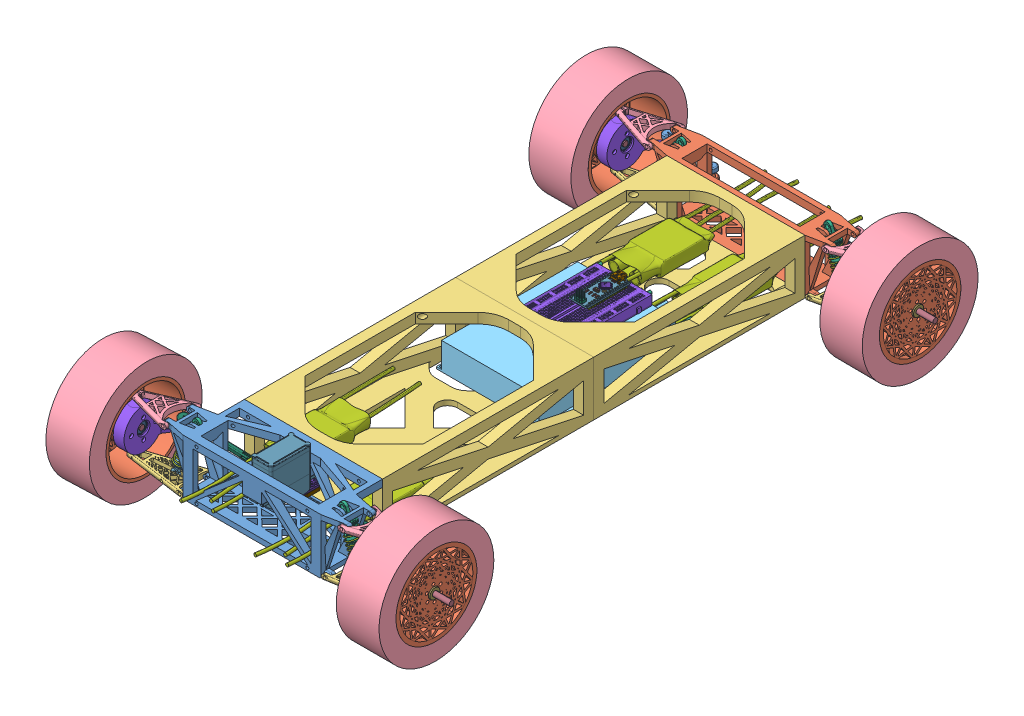
SolidWorks assembly corr, configuration Default. Lengths in mm.
Overall size (361.58 158.9 635.76).
113 component instances, 44 part files, 87 mates.
Components (placement in the parent):
- front subframe-1: front subframe [Default] at (44.8568 124.9262 411.3933) x (0 0 -1) z (1 0 0) size (61.1 55 184.24)
- rear subframe-1: rear subframe [Default] at (250.5037 124.9262 -151.6436) x (0 0 1) z (-1 0 0) size (45 55 184.24)
- lower_control_arm_front-1: lower_control_arm_front [Default] at (12.1352 184.7934 -110.1751) x (0 0 -1) z (-0.99961 -0.027933 0) size (37.5 5.03 71.27)
- lower_control_arm_front-2: lower_control_arm_front [Default] at (12.207 180.9628 369.9249) x (0 0 -1) z (-0.99611 -0.08812 0) size (37.5 5.03 71.27)
- lower_control_arm_front-3: lower_control_arm_front [Default] at (283.1703 186.8095 -110.1751) x (0 0 1) z (0.999993 0.003801 0) size (37.5 5.03 71.27)
- lower_control_arm_front-4: lower_control_arm_front [Default] at (283.2294 183.9874 369.9249) x (0 0 1) z (0.999175 -0.040609 0) size (37.5 5.03 71.27)
- upper_control_arm_front-1: upper_control_arm_front [Default] at (15.5255 232.3308 -110.1751) x (0 0 1) z (-0.999846 0.017523 0) size (35.03 5.03 51.52)
- upper_control_arm_front-2: upper_control_arm_front [Default] at (15.8477 228.503 369.9249) x (0 0 1) z (-0.997504 -0.070606 0) size (35.03 5.03 51.52)
- upper_control_arm_front-3: upper_control_arm_front [Default] at (279.7954 231.5247 369.9249) x (0 0 -1) z (1 -0.000997 0) size (35.03 5.03 51.52)
- upper_control_arm_front-4: upper_control_arm_front [Default] at (279.8688 234.3481 -110.1751) x (0 0 -1) z (0.997963 0.06379 0) size (35.03 5.03 51.52)
- coilover-1: coilover [Default] at (40.225 170.2681 389.3312) x (0.928908 -0.37031 0) z (0.37031 0.928908 0) size (15.15 15.15 65.67)
  - strut bottom-1: strut bottom [Default] at (8.2738 19.4064 16.0769) size (13 13 37)
  - strut top-1: strut top [Default] at (8.2738 20.4064 60.2501) x (0.996359 -0.085262 0) z (0.085262 0.996359 0) size (14.01 35 14.01)
  - spring-1: spring [Default] at (8.2738 20.4064 29.0769) x (1 0 0) z (0 -1 0) size (13.4 33.17 15.01)
- coilover-2: coilover [Default] at (239.504 166.1902 -90.7688) x (0.935849 0.352401 0) z (-0.352401 0.935849 0) size (15.15 15.15 65.67)
  - strut bottom-1: strut bottom [Default] at (8.2738 19.4064 16.0769) size (13 13 37)
  - strut top-1: strut top [Default] at (8.2738 20.4064 60.2501) x (0.996359 -0.085262 0) z (0.085262 0.996359 0) size (14.01 35 14.01)
  - spring-1: spring [Default] at (8.2738 20.4064 29.0769) x (1 0 0) z (0 -1 0) size (13.4 33.17 15.01)
- coilover-3: coilover [Default] at (255.1275 171.2229 348.5185) x (-0.931225 -0.364446 0) z (-0.364446 0.931225 0) size (15.15 15.15 65.67)
  - strut bottom-1: strut bottom [Default] at (8.2738 19.4064 16.0769) size (13 13 37)
  - strut top-1: strut top [Default] at (8.2738 20.4064 60.2501) x (0.996359 -0.085262 0) z (0.085262 0.996359 0) size (14.01 35 14.01)
  - spring-1: spring [Default] at (8.2738 20.4064 29.0769) x (1 0 0) z (0 -1 0) size (13.4 33.17 15.01)
- coilover-4: coilover [Default] at (40.0876 171.6564 -90.7688) x (0.926996 -0.375072 0) z (0.375072 0.926996 0) size (15.15 15.15 65.67)
  - strut bottom-1: strut bottom [Default] at (8.2738 19.4064 16.0769) size (13 13 37)
  - strut top-1: strut top [Default] at (8.2738 20.4064 60.2501) x (0.996359 -0.085262 0) z (0.085262 0.996359 0) size (14.01 35 14.01)
  - spring-1: spring [Default] at (8.2738 20.4064 29.0769) x (1 0 0) z (0 -1 0) size (13.4 33.17 15.01)
- pside_front_knuckle-1: pside_front_knuckle [Default] at (20.5945 204.7916 369.7511) x (0.008771 -0.999959 -0.002056) z (-0.026502 0.001823 -0.999647) size (55 23.73 55.17)
- pside_front_knuckle-2: pside_front_knuckle [Default] at (20.4171 208.6285 -110.1416) x (0.010097 -0.999949 0.000397) z (0.005118 -0.000345 -0.999987) size (55 23.73 55.17)
- dside_front_knuckle-1: dside_front_knuckle [Default] at (274.9294 207.8222 369.9864) x (-0.01 -0.99995 0.000728) z (-0.009385 -0.000634 -0.999956) size (55 23.73 55.17)
- dside_front_knuckle-2: dside_front_knuckle [Default] at (274.9235 210.6426 -110.1646) x (-0.009923 -0.999951 0.000125) z (-0.001612 -0.000109 -0.999999) size (55 23.73 55.17)
- d3536-1: d3536 [Default] at (8.3914 187.1271 354.2371) x (0.026502 -0.001823 0.999647) z (-0.008771 0.999959 0.002056) size (46.45 53.5 46.45)
  - bottom_case-1: bottom_case [Default] at (15.7997 3.4433 17.5887) size (35 8.57 35)
  - middle_case-1: middle_case [Default] at (15.7997 -15.0567 17.5887) x (-0.998365 0 0.05716) z (-0.05716 0 -0.998365) size (35 18 35)
  - top_case-1: top_case [Default] at (15.7997 -15.0567 17.5887) x (-0.907758 0 0.419495) z (0.419495 0 0.907758) size (35 9.5 35)
  - shaft-1: shaft [Default] at (15.7997 -41.0567 17.5887) x (-0.024609 0 -0.999697) z (0.999697 0 -0.024609) size (5 53.5 5)
- d3536-2: d3536 [Default] at (286.7172 192.938 -94.3819) x (-0.001612 -0.000109 -0.999999) z (0.009923 0.999951 -0.000125) size (46.45 53.5 46.45)
  - bottom_case-1: bottom_case [Default] at (15.7997 3.4433 17.5887) size (35 8.57 35)
  - middle_case-1: middle_case [Default] at (15.7997 -15.0567 17.5887) x (-0.998365 0 0.05716) z (-0.05716 0 -0.998365) size (35 18 35)
  - top_case-1: top_case [Default] at (15.7997 -15.0567 17.5887) x (-0.907758 0 0.419495) z (0.419495 0 0.907758) size (35 9.5 35)
  - shaft-1: shaft [Default] at (15.7997 -41.0567 17.5887) x (-0.024609 0 -0.999697) z (0.999697 0 -0.024609) size (5 53.5 5)
- d3536-3: d3536 [Default] at (8.733 190.9146 -125.9952) x (-0.005118 0.000345 0.999987) z (-0.010097 0.999949 -0.000397) size (46.45 53.5 46.45)
  - bottom_case-1: bottom_case [Default] at (15.7997 3.4433 17.5887) size (35 8.57 35)
  - middle_case-1: middle_case [Default] at (15.7997 -15.0567 17.5887) x (-0.998365 0 0.05716) z (-0.05716 0 -0.998365) size (35 18 35)
  - top_case-1: top_case [Default] at (15.7997 -15.0567 17.5887) x (-0.907758 0 0.419495) z (0.419495 0 0.907758) size (35 9.5 35)
  - shaft-1: shaft [Default] at (15.7997 -41.0567 17.5887) x (-0.024609 0 -0.999697) z (0.999697 0 -0.024609) size (5 53.5 5)
- d3536-4: d3536 [Default] at (286.844 190.1249 385.6862) x (-0.009385 -0.000634 -0.999956) z (0.01 0.99995 -0.000728) size (46.45 53.5 46.45)
  - bottom_case-1: bottom_case [Default] at (15.7997 3.4433 17.5887) size (35 8.57 35)
  - middle_case-1: middle_case [Default] at (15.7997 -15.0567 17.5887) x (-0.998365 0 0.05716) z (-0.05716 0 -0.998365) size (35 18 35)
  - top_case-1: top_case [Default] at (15.7997 -15.0567 17.5887) x (-0.907758 0 0.419495) z (0.419495 0 0.907758) size (35 9.5 35)
  - shaft-1: shaft [Default] at (15.7997 -41.0567 17.5887) x (-0.024609 0 -0.999697) z (0.999697 0 -0.024609) size (5 53.5 5)
- LewanSoul LD-20M  Servo 20kg-1: LewanSoul LD-20M  Servo 20kg [Default] at (147.6802 243.8348 358.3749) x (0 0 -1) z (-1 0 0) size (55.1 45.65 20.12)
- steering arm link-1: steering arm link [Default] at (230.7612 202.8931 337.2388) x (0.99528 0.093085 0.027436) z (0.008631 0.196686 -0.980429) size (77 5 9)
- steering arm link-2: steering arm link [Default] at (63.5262 201.4549 336.7754) x (0.998595 -0.049529 -0.018834) z (-0.011198 0.15015 -0.9886) size (77 5 9)
- steering arm center-1: steering arm center [Default] at (147.2842 186.5681 335.5749) size (109 12 9)
- Servo Mount - Arm Metal Standard-1: Servo Mount - Arm Metal Standard [Défaut] at (147.6802 196.3848 348.4249) x (0.999935 0 -0.011364) z (0 1 0) size (12.43 33.73 5.41)
- steering servo attachment-1: steering servo attachment [Default] at (147.6802 196.3848 348.4249) x (-0.999935 0 0.011364) z (0 -1 0) size (7.5 19.25 3.5)
- rear toe arm-1: rear toe arm [Default] at (238.3086 209.8989 -137.8087) x (0.982379 -0.033336 -0.183902) z (-0.184459 -0.01443 -0.982734) size (64 5 9)
- rear toe arm-2: rear toe arm [Default] at (56.9268 208.879 -137.6028) x (0.980643 0.070066 0.182838) z (0.180365 0.040187 -0.982778) size (64 5 9)
- 8th scale wheel-2: 8th scale wheel [Default] at (309.9261 207.472 369.6581) x (0.01095 0.170873 0.985232) z (-0.999906 0.010006 0.009378) size (89 89 42)
- 8th scale wheel-3: 8th scale wheel [Default] at (309.9218 210.2953 -110.2209) x (-0.006592 -0.768145 0.640241) z (-0.999949 0.009923 0.00161) size (89 89 42)
- 8th scale wheel-4: 8th scale wheel [Default] at (-14.5806 208.275 -110.3206) x (0.003324 0.169907 -0.985454) z (0.999936 0.010099 0.005114) size (89 89 42)
- 8th scale wheel-5: 8th scale wheel [Default] at (-14.3918 204.4828 370.6781) x (-0.010227 -0.767055 -0.6415) z (0.99961 0.008822 -0.026485) size (89 89 42)
- middle subframe-4: middle subframe [Default] at (147.6802 181.5681 12.0749) size (137 57.18 209.5)
- middle subframe-5: middle subframe [Default] at (147.6802 181.5681 221.5749) size (137 57.18 209.5)
- 8th scale tire-5: 8th scale tire [Default] at (270.9298 207.8622 370.0239) x (-0.005178 0.357718 -0.933815) z (-0.012698 -0.933776 -0.357633) size (115 42 115)
- 8th scale tire-6: 8th scale tire [Default] at (24.593 204.8269 369.6452) x (0.02728 -0.509931 0.859783) z (-0.00592 -0.86017 -0.509973) size (115 42 115)
- 8th scale tire-7: 8th scale tire [Default] at (24.4169 208.6689 -110.1211) x (-0.000567 -0.406519 0.913642) z (0.011306 -0.913587 -0.406487) size (115 42 115)
- 8th scale tire-8: 8th scale tire [Default] at (270.9237 210.6823 -110.1581) x (0.001889 0.34285 -0.939388) z (-0.009874 -0.939338 -0.342851) size (115 42 115)
- Zee3200mahCase-1: Zee3200mahCase [Default] at (38.1015 164.6613 84.8893) x (-1 0 0) z (0 -1 0) size (107 155 27)
- Zee3200mah-2: Zee3200mah [Default] at (176.1812 188.5681 86.3893) x (0 0 1) z (-1 0 0) size (153 20 44)
- Zee3200mah-3: Zee3200mah [Default] at (127.1812 188.5681 86.3893) x (0 0 1) z (-1 0 0) size (153 20 44)
- Hobbyking 60A ESC-1: Hobbyking 60A ESC [Default] at (106.7323 191.308 286.8707) x (0 0 1) z (-1 0 0) size (215.37 15 36.72)
- Hobbyking 60A ESC-2: Hobbyking 60A ESC [Default] at (186.2753 187.7184 292.8407) x (0 0 1) z (-1 0 0) size (215.37 15 36.72)
- Hobbyking 60A ESC-3: Hobbyking 60A ESC [Default] at (178.7238 189.4946 -56.0447) x (0 0 -1) z (1 0 0) size (215.37 15 36.72)
- Hobbyking 60A ESC-4: Hobbyking 60A ESC [Default] at (117.1129 190.2764 -54.4214) x (0 0 -1) z (1 0 0) size (215.37 15 36.72)
- HalfBreadboard-1: HalfBreadboard [Default] at (192.3017 218.8181 61.6331) size (56.08 9.51 83.01)
- arduino nano-1: arduino nano [Default] at (158.518 224.9181 63.6156) x (0 0 -1) z (1 0 0) size (45 18.6 18)
  - arduino nano.STEP-1: arduino nano.STEP [Default] at origin size (45 18.6 18)
    - MINIUSB - MEASURED.STEP-1: MINIUSB - MEASURED.STEP [Default] at (38.98 1.65 -7.62) x (0 0 1) z (-1 0 0) size (10.9 4.8 10.4)
      - MINIUSBSHELL.STEP-1: MINIUSBSHELL.STEP [Default] at origin size (10.9 3.75 9.4)
      - MINIUSBCORE.STEP-1: MINIUSBCORE.STEP [Default] at (0 0 6.7) x (-1 0 0) z (0 0 -1) size (7.7 4.5 8.2)
      - MINI USB CONTACT.STEP-1: MINI USB CONTACT.STEP [Default] at (-1.6 0 5.7) x (-1 0 0) z (0 0 -1) size (0.51 2.55 9.4)
      - MINI USB CONTACT.STEP-2: MINI USB CONTACT.STEP [Default] at (-0.8 0 5.7) x (-1 0 0) z (0 0 -1) size (0.51 2.55 9.4)
      - MINI USB CONTACT.STEP-3: MINI USB CONTACT.STEP [Default] at (0 0 5.7) x (-1 0 0) z (0 0 -1) size (0.51 2.55 9.4)
      - MINI USB CONTACT.STEP-4: MINI USB CONTACT.STEP [Default] at (0.8 0 5.7) x (-1 0 0) z (0 0 -1) size (0.51 2.55 9.4)
      - MINI USB CONTACT.STEP-5: MINI USB CONTACT.STEP [Default] at (1.6 0 5.7) x (-1 0 0) z (0 0 -1) size (0.51 2.55 9.4)
    - reset button.STEP-1: reset button.STEP [Default] at (15.25 1.6 -8.05) x (0 0 -1) z (1 0 0) size (5.2 2.15 3)
      - reset core.STEP-1: reset core.STEP [Default] at origin size (5.2 2.15 2.8)
      - reset shell.STEP-1: reset shell.STEP [Default] at (0 1.65 0) x (0 0 1) z (-1 0 0) size (3 1.65 4)
    - nano-board.STEP-1: nano-board.STEP [Default] at origin size (43.2 4.6 18)
    - 2pin_header__02.STEP-1: 2pin_header__02.STEP [Default] at (-1.143 1.6 -7.62) size (5 11.75 2.54)
    - 2pin_header__02.STEP-2: 2pin_header__02.STEP [Default] at (-1.143 1.6 -5.08) size (5 11.75 2.54)
    - 2pin_header__02.STEP-3: 2pin_header__02.STEP [Default] at (-1.143 1.6 -10.16) size (5 11.75 2.54)
    - 15pin_header__.STEP-1: 15pin_header__.STEP [Default] x (0 0 1) z (1 0 0) size (2.54 11.75 38.1)
    - 15pin_header__.STEP-2: 15pin_header__.STEP [Default] at (0 0 -15.24) x (0 0 1) z (1 0 0) size (2.54 11.75 38.1)
    - atmega328.STEP-1: atmega328.STEP [Default] at (23.85 1.75 -7.62) x (-0.707107 0 0.707107) z (-0.707107 0 -0.707107) size (10 1.1 10)
    - ftdi FT232rl.STEP-1: ftdi FT232rl.STEP [Default] at (29.05 0 -7.67) x (0 0 -1) z (-1 0 0) size (9.25 1.9 10.2)
    - smt_resistor222.STEP-1: smt_resistor222.STEP [Default] at (21.86 0 -5.8) x (0 0 -1) z (-1 0 0) size (1.7 0.6 3.8)
    - smt_resistor222.STEP-2: smt_resistor222.STEP [Default] at (21.86 0 -9) x (0 0 -1) z (-1 0 0) size (1.7 0.6 3.8)
    - smt_resistor222.STEP-3: smt_resistor222.STEP [Default] at (36.75 0 -7.6) x (0 0 -1) z (-1 0 0) size (1.7 0.6 3.8)
    - smt_resistor222.STEP-4: smt_resistor222.STEP [Default] at (36.75 0 -12) x (0 0 -1) z (-1 0 0) size (1.7 0.6 3.8)
    - smt_resistor222.STEP-5: smt_resistor222.STEP [Default] at (8.2 0 -2.6) x (0 0 -1) z (-1 0 0) size (1.7 0.6 3.8)
    - led.STEP-1: led.STEP [Default] at (10.4 1.6 -2.8) size (4 0.85 1.47)
    - led.STEP-2: led.STEP [Default] at (10.4 1.6 -5.55) size (4 0.85 1.47)
    - led.STEP-3: led.STEP [Default] at (10.4 1.6 -12.5) size (4 0.85 1.47)
    - led.STEP-4: led.STEP [Default] at (10.4 1.6 -9.05) size (4 0.85 1.47)
    - 16mhz crystal - measured.STEP-1: 16mhz crystal - measured.STEP [Default] at (18.5113 1.6 -3.5541) x (0.707107 0 0.707107) z (-0.707107 0 0.707107) size (3.4 0.8 2)
    - cap106C.STEP-1: cap106C.STEP [Default] at (37.2 0 -3.3) x (0 0 1) z (1 0 0) size (1.7 1.81 4)
    - cap106C.STEP-2: cap106C.STEP [Default] at (7.9 0 -5.6) x (0 0 -1) z (-1 0 0) size (1.7 1.81 4)
    - nano - reg.STEP-1: nano - reg.STEP [Default] at (6.1 0 -10.16) x (0 0 -1) z (-1 0 0) size (6.5 1.69 8.3)
    - NANO DIODE.STEP-1: NANO DIODE.STEP [Default] at (11.43 0 -4.2) x (0 0 1) z (1 0 0) size (4.92 1.39 1.7)
    - 189 RESISTOR PACK.STEP-1: 189 RESISTOR PACK.STEP [Default] at (15.75 0 -10.85) x (0 0 1) z (1 0 0) size (3.2 0.46 3)
    - 102 RESISTOR PACK.STEP-1: 102 RESISTOR PACK.STEP [Default] at (15.75 0 -5.2) x (0 0 1) z (1 0 0) size (3.2 0.46 3)
Mates (geometry in assembly coordinates):
- Coincident6: coincident anti-aligned: circle of rear subframe-1; circle of lower_control_arm_front-1
- Coincident7: coincident aligned: circle of rear subframe-1; circle of lower_control_arm_front-3
- Coincident8: coincident aligned: circle of front subframe-1; circle of lower_control_arm_front-2
- Coincident9: coincident anti-aligned: circle of front subframe-1; circle of lower_control_arm_front-4
- Coincident10: coincident aligned: circle of front subframe-1; circle of upper_control_arm_front-3
- Coincident11: coincident aligned: circle of rear subframe-1; circle of upper_control_arm_front-4
- Coincident12: coincident aligned: circle of rear subframe-1; circle of upper_control_arm_front-1
- Coincident13: coincident aligned: circle of front subframe-1; circle of upper_control_arm_front-2
- Concentric1: concentric: sphere of lower_control_arm_front-4; sphere of dside_front_knuckle-1
- Concentric2: concentric: sphere of upper_control_arm_front-3; sphere of dside_front_knuckle-1
- Concentric3: concentric: sphere of lower_control_arm_front-3; sphere of dside_front_knuckle-2
- Concentric4: concentric: sphere of upper_control_arm_front-4; sphere of dside_front_knuckle-2
- Concentric5: concentric: sphere of lower_control_arm_front-2; sphere of pside_front_knuckle-1
- Concentric6: concentric: sphere of upper_control_arm_front-2; sphere of pside_front_knuckle-1
- Concentric7: concentric: sphere of lower_control_arm_front-1; sphere of pside_front_knuckle-2
- Concentric8: concentric: sphere of upper_control_arm_front-1; sphere of pside_front_knuckle-2
- Concentric9: concentric aligned: circle of lower_control_arm_front-3; circle of coilover-2/strut bottom-1
- Coincident14: coincident anti-aligned: plane of lower_control_arm_front-3 through (283.346 140.5905 -112.1751) normal (0 0 1); plane of coilover-2/strut bottom-1 through (241.5815 184.1514 -112.1751) normal (0 0 -1)
- Concentric10: concentric anti-aligned: circle of lower_control_arm_front-1; circle of coilover-4/strut bottom-1
- Coincident15: coincident anti-aligned: plane of lower_control_arm_front-1 through (13.4262 138.5922 -112.1751) normal (0 0 1); plane of coilover-4/strut bottom-1 through (53.7874 183.4563 -112.1751) normal (0 0 -1)
- Concentric11: concentric anti-aligned: circle of lower_control_arm_front-4; circle of coilover-3/strut bottom-1
- Coincident16: coincident anti-aligned: plane of lower_control_arm_front-4 through (281.3525 137.8062 367.9249) normal (0 0 1); plane of coilover-3/strut bottom-1 through (241.5636 183.1787 367.9249) normal (0 0 -1)
- Concentric12: concentric anti-aligned: circle of lower_control_arm_front-2; circle of coilover-1/strut bottom-1
- Coincident17: coincident anti-aligned: plane of lower_control_arm_front-2 through (16.2798 134.9233 367.9249) normal (0 0 1); plane of coilover-1/strut bottom-1 through (53.864 182.1382 367.9249) normal (0 0 -1)
- Concentric13: concentric anti-aligned: circle of pside_front_knuckle-1; circle of d3536-1/bottom_case-1
- Concentric14: concentric anti-aligned: circle of pside_front_knuckle-1; circle of d3536-1/bottom_case-1
- Coincident18: coincident anti-aligned: plane of pside_front_knuckle-1 through (20.5945 204.7916 369.7511) normal (-0.99961 -0.008822 0.026485); plane of d3536-1/bottom_case-1 through (20.5945 204.7916 369.7511) normal (0.99961 0.008822 -0.026485)
- Concentric16: concentric aligned: circle of dside_front_knuckle-1; circle of d3536-4/bottom_case-1
- Concentric17: concentric aligned: circle of dside_front_knuckle-1; circle of d3536-4/bottom_case-1
- Coincident19: coincident anti-aligned: plane of dside_front_knuckle-1 through (274.9294 207.8222 369.9864) normal (0.999906 -0.010006 -0.009378); plane of d3536-4/bottom_case-1 through (274.9294 207.8222 369.9864) normal (-0.999906 0.010006 0.009378)
- Concentric18: concentric aligned: circle of dside_front_knuckle-2; circle of d3536-2/bottom_case-1
- Concentric19: concentric aligned: circle of dside_front_knuckle-2; circle of d3536-2/bottom_case-1
- Coincident21: coincident anti-aligned: plane of dside_front_knuckle-2 through (274.9235 210.6426 -110.1646) normal (0.999949 -0.009923 -0.00161); plane of d3536-2/bottom_case-1 through (274.9235 210.6426 -110.1646) normal (-0.999949 0.009923 0.00161)
- Concentric20: concentric anti-aligned: circle of pside_front_knuckle-2; circle of d3536-3/bottom_case-1
- Concentric21: concentric anti-aligned: circle of pside_front_knuckle-2; circle of d3536-3/bottom_case-1
- Coincident22: coincident anti-aligned: plane of pside_front_knuckle-2 through (20.4171 208.6285 -110.1416) normal (-0.999936 -0.010099 -0.005114); plane of d3536-3/bottom_case-1 through (20.4171 208.6285 -110.1416) normal (0.999936 0.010099 0.005114)
- Concentric22: concentric anti-aligned: circle of Servo Mount - Arm Metal Standard-1; circle of steering servo attachment-1
- Concentric23: concentric anti-aligned: circle of Servo Mount - Arm Metal Standard-1; circle of steering servo attachment-1
- Coincident23: coincident anti-aligned: plane of Servo Mount - Arm Metal Standard-1 through (147.4075 196.3848 324.4264) normal (0 -1 0); plane of steering servo attachment-1 through (147.6802 196.3848 348.4249) normal (0 1 0)
- Coincident24: coincident anti-aligned: plane of front subframe-1 through (44.8568 215.4848 411.3933) normal (0 -1 0); plane of LewanSoul LD-20M  Servo 20kg-1 through (142.6802 215.4848 333.3249) normal (0 1 0)
- Coincident25: coincident aligned: line of front subframe-1 through (157.2302 215.4848 331.3249) axis (0 1 0); line of LewanSoul LD-20M  Servo 20kg-1 through (157.2302 212.8348 331.3249) axis (0 1 0)
- Parallel1: parallel anti-aligned: line of front subframe-1 through (138.1302 215.4848 331.3249) axis (1 0 0); line of LewanSoul LD-20M  Servo 20kg-1 through (151.1802 212.8348 330.8249) axis (-1 0 0)
- Concentric24: concentric anti-aligned: circle of LewanSoul LD-20M  Servo 20kg-1; circle of Servo Mount - Arm Metal Standard-1
- Coincident28: coincident anti-aligned: plane of LewanSoul LD-20M  Servo 20kg-1 through (147.6802 198.1848 348.4249) normal (0 -1 0); plane of Servo Mount - Arm Metal Standard-1 through (147.6802 198.1848 348.4249) normal (0 1 0)
- Coincident29: coincident anti-aligned: plane of front subframe-1 through (223.1802 186.5681 379.4249) normal (0 1 0); plane of steering arm center-1 through (147.2842 186.5681 335.5749) normal (0 -1 0)
- Tangent2: tangent anti-aligned: cylinder of steering arm center-1 through (147.2842 195.0681 335.5749) axis (0 -1 0) radius 1.5; plane of steering servo attachment-1 through (145.9304 192.8848 348.4447) normal (0.999935 0 -0.011364)
- Coincident31: coincident anti-aligned: plane of front subframe-1 through (44.8568 191.5681 337.5749) normal (0 0 -1); plane of steering arm center-1 through (147.2842 191.5681 337.5749) normal (0 0 1)
- Concentric25: concentric: sphere of steering arm link-1; sphere of steering arm center-1
- Concentric26: concentric: sphere of dside_front_knuckle-1; sphere of steering arm link-1
- Concentric27: concentric: sphere of pside_front_knuckle-1; sphere of steering arm link-2
- Concentric28: concentric: sphere of steering arm link-2; sphere of steering arm center-1
- Concentric29: concentric: sphere of dside_front_knuckle-2; sphere of rear toe arm-1
- Concentric30: concentric: sphere of rear subframe-1; sphere of rear toe arm-1
- Concentric31: concentric: sphere of rear subframe-1; sphere of rear toe arm-2
- Concentric32: concentric: sphere of pside_front_knuckle-2; sphere of rear toe arm-2
- Concentric33: concentric anti-aligned: circle of d3536-4/top_case-1; circle of 8th scale wheel-2
- Concentric34: concentric anti-aligned: circle of d3536-4/top_case-1; circle of 8th scale wheel-2
- Coincident32: coincident anti-aligned: plane of d3536-4/top_case-1 through (307.9263 207.492 369.6769) normal (0.999906 -0.010006 -0.009378); plane of 8th scale wheel-2 through (307.9263 207.492 369.6769) normal (-0.999906 0.010006 0.009378)
- Concentric35: concentric anti-aligned: circle of d3536-1/top_case-1; circle of 8th scale wheel-5
- Concentric36: concentric anti-aligned: circle of d3536-1/top_case-1; circle of 8th scale wheel-5
- Coincident33: coincident anti-aligned: plane of d3536-1/top_case-1 through (-12.3926 204.5005 370.6251) normal (-0.99961 -0.008822 0.026485); plane of 8th scale wheel-5 through (-12.3926 204.5005 370.6251) normal (0.99961 0.008822 -0.026485)
- Concentric37: concentric anti-aligned: circle of d3536-3/top_case-1; circle of 8th scale wheel-4
- Concentric38: concentric anti-aligned: circle of d3536-3/top_case-1; circle of 8th scale wheel-4
- Coincident34: coincident anti-aligned: plane of d3536-3/top_case-1 through (-12.5807 208.2952 -110.3104) normal (-0.999936 -0.010099 -0.005114); plane of 8th scale wheel-4 through (-12.5807 208.2952 -110.3104) normal (0.999936 0.010099 0.005114)
- Concentric39: concentric anti-aligned: circle of d3536-2/top_case-1; circle of 8th scale wheel-3
- Concentric40: concentric anti-aligned: circle of d3536-2/top_case-1; circle of 8th scale wheel-3
- Coincident35: coincident anti-aligned: plane of d3536-2/top_case-1 through (307.9219 210.3151 -110.2177) normal (0.999949 -0.009923 -0.00161); plane of 8th scale wheel-3 through (307.9219 210.3151 -110.2177) normal (-0.999949 0.009923 0.00161)
- Coincident49: coincident anti-aligned: line of rear subframe-1 through (79.1802 236.5681 -92.6751) axis (1 0 0); line of middle subframe-4 through (216.1802 236.5681 -92.6751) axis (-1 0 0)
- Coincident50: coincident aligned: line of rear subframe-1 through (216.1802 231.5681 -92.6751) axis (0 -1 0); line of middle subframe-4 through (216.1802 236.5681 -92.6751) axis (0 -1 0)
- Coincident51: coincident anti-aligned: line of front subframe-1 through (216.1802 236.5681 326.3249) axis (-1 0 0); line of middle subframe-5 through (79.1802 236.5681 326.3249) axis (1 0 0)
- Coincident52: coincident aligned: line of front subframe-1 through (216.1802 236.5681 326.3249) axis (0 -1 0); line of middle subframe-5 through (216.1802 236.5681 326.3249) axis (0 -1 0)
- Coincident53: coincident anti-aligned: line of middle subframe-4 through (79.1802 236.5681 116.8249) axis (1 0 0); line of middle subframe-5 through (216.1802 236.5681 116.8249) axis (-1 0 0)
- Coincident54: coincident aligned: line of middle subframe-4 through (216.1802 236.5681 116.8249) axis (0 -1 0); line of middle subframe-5 through (216.1802 236.5681 116.8249) axis (0 -1 0)
- Coincident55: coincident aligned: circle of 8th scale wheel-2; circle of 8th scale tire-5
- Coincident56: coincident aligned: circle of 8th scale wheel-3; circle of 8th scale tire-8
- Coincident57: coincident aligned: circle of 8th scale wheel-5; circle of 8th scale tire-6
- Coincident58: coincident aligned: circle of 8th scale wheel-4; circle of 8th scale tire-7
- Coincident59: coincident anti-aligned: plane of middle subframe-5 through (147.6802 186.5681 221.5749) normal (0 1 0); plane of Zee3200mahCase-1 through (38.1015 186.5681 154.8893) normal (0 -1 0)
- Parallel2: parallel anti-aligned: plane of middle subframe-4 through (89.1802 186.5681 106.8249) normal (1 0 0); plane of Zee3200mahCase-1 through (103.1812 164.6613 154.8893) normal (-1 0 0)
- Coincident61: coincident anti-aligned: plane of Zee3200mahCase-1 through (198.1812 164.6613 -80.7984) normal (-1 0 0); plane of Zee3200mah-2 through (198.1812 208.5681 19.8893) normal (1 0 0)
- Coincident62: coincident anti-aligned: plane of Zee3200mahCase-1 through (38.1015 188.5681 -80.7984) normal (0 1 0); plane of Zee3200mah-2 through (176.1812 188.5681 86.3893) normal (0 -1 0)
- Coincident63: coincident aligned: plane of Zee3200mahCase-1 through (173.6812 210.0681 19.8893) normal (0 0 -1); plane of Zee3200mah-2 through (198.1812 208.5681 19.8893) normal (0 0 -1)
- Coincident64: coincident anti-aligned: plane of Zee3200mahCase-1 through (105.1812 164.6613 -80.7984) normal (1 0 0); plane of Zee3200mah-3 through (105.1812 208.5681 19.8893) normal (-1 0 0)
- Coincident65: coincident anti-aligned: plane of Zee3200mahCase-1 through (38.1015 188.5681 -80.7984) normal (0 1 0); plane of Zee3200mah-3 through (127.1812 188.5681 86.3893) normal (0 -1 0)
- Coincident66: coincident aligned: plane of Zee3200mahCase-1 through (173.6812 210.0681 19.8893) normal (0 0 -1); plane of Zee3200mah-3 through (149.1812 208.5681 19.8893) normal (0 0 -1)
- Coincident67: coincident anti-aligned: plane of Zee3200mahCase-1 through (38.1015 213.5681 154.8893) normal (0 1 0); plane of HalfBreadboard-1 through (150.3917 213.5681 19.7231) normal (0 -1 0)
- Coincident69: coincident anti-aligned: plane of HalfBreadboard-1 through (150.3917 223.0681 19.7231) normal (0 1 0); plane of arduino nano-1/arduino nano.STEP-1/ftdi FT232rl.STEP-1 through (153.348 223.0681 39.6656) normal (0 -1 0)
